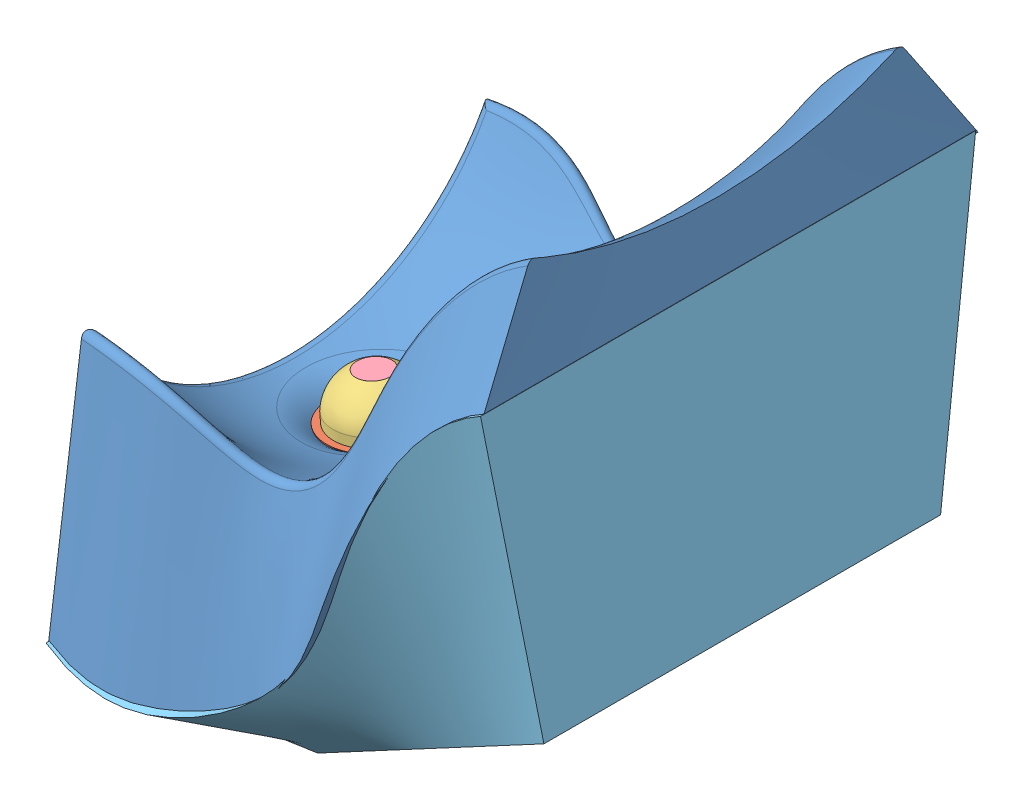
SolidWorks assembly Assem1, configuration Default. Lengths in mm.
Overall size (71.68 95.53 78.72).
6 component instances, 5 part files, 0 mates.
Components (placement in the parent):
- Magnetic Force Sensor with Casing Assembly-1: Magnetic Force Sensor with Casing Assembly [Default] at (-36.1517 26.1395 1.3179) size (68.77 82.29 78.14)
  - Funnel with Opening for Elastomer-1: Funnel with Opening for Elastomer [Default] at (-37.7843 -40.7454 17.3257) size (68.77 82.29 78.14)
  - Elastomer PCB Interface-1: Elastomer PCB Interface [Default] at (-26.1092 -46.4544 17.3299) x (0.988057 0.086959 -0.127205) z (0.126049 0.018684 0.991848) size (14 3.2 14)
  - Silicon Elastomer-1: Silicon Elastomer [Default] at (-26.251 -44.8607 17.3179) x (0.996065 0.088627 -0.000333) z (0.088627 -0.996037 0.0075) size (12 12 7.9)
  - Neodymium Magnet-2: Neodymium Magnet [Default] at (-26.7739 -38.9841 17.2736) x (0.996065 0.088627 -0.000333) z (-0.000333 0.0075 0.999972) size (5 2 5)
- Electronics Case UrinDX Tagleed-1: Electronics Case UrinDX Tagleed [Default] at (-73.89 -14.1785 19.037) size (66.7 76.33 78.54)
